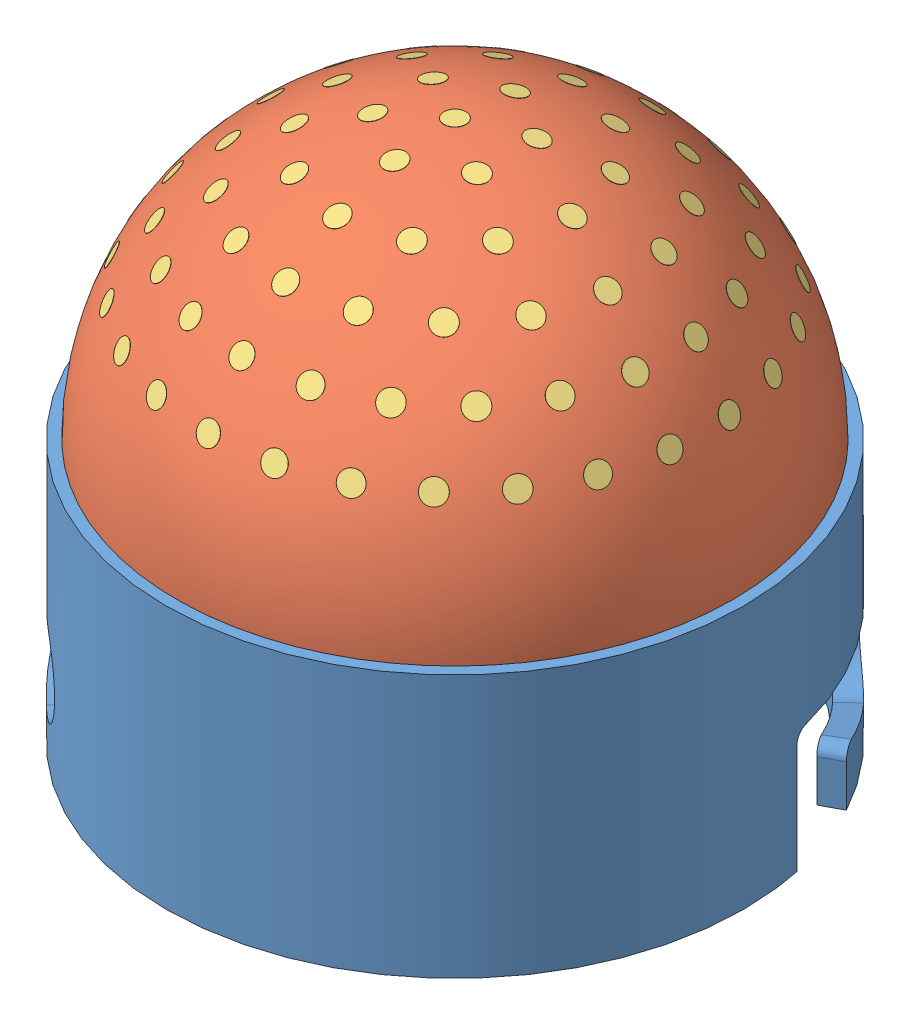
SolidWorks assembly tactile_dome_outer, configuration Default. Lengths in mm.
Overall size (29 29.2 29).
3 component instances, 3 part files, 3 mates.
Components (placement in the parent):
- dome_outer_rigidframe-1: dome_outer_rigidframe [Default] at origin size (29 16.65 29)
- dome_outer_gel-1: dome_outer_gel [Default] at origin size (25.4 12.69 25.4)
- dome_outer_markers-1: dome_outer_markers [Default] at origin size (22.95 7.51 22.91)
Mates (geometry in assembly coordinates):
- Coincident1: coordinate: point of dome_outer_rigidframe-1
- Coincident2: coordinate: unknown of dome_outer_gel-1
- Coincident3: coordinate: unknown of dome_outer_markers-1
